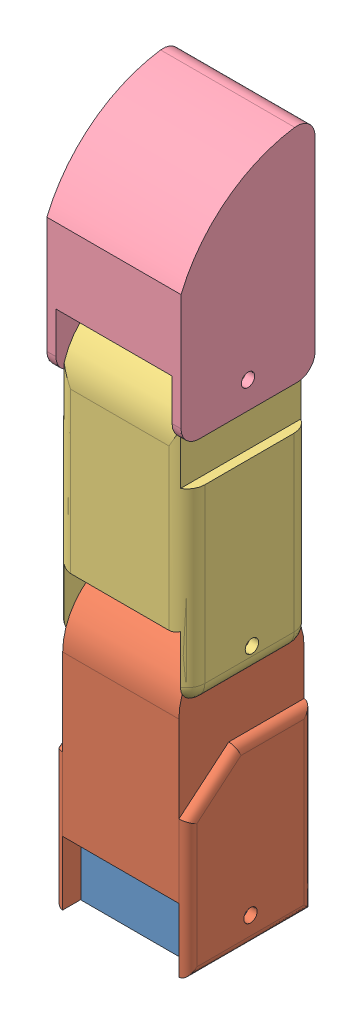
SolidWorks assembly finger_assembly_no_pins_2_moveable_joint, configuration Default. Lengths in mm.
Overall size (15 76.91 15).
4 component instances, 4 part files, 9 mates.
Components (placement in the parent):
- connection_to_motor-1: connection_to_motor [Default] at (-1.3444 3.3196 4.6567) size (13 7.55 9.9)
- end_of_finger-1: end_of_finger [Default] at (-2.3444 3.3736 16.6064) x (0 -1 0) z (1 0 0) size (32 14 15)
- middle_of_finger-1: middle_of_finger [Default] at (12.6556 29.3736 2.7087) x (0 -1 0) z (-1 0 0) size (31.73 14 15)
- tip_of_finger-1: tip_of_finger [Default] at (-2.3444 55.3736 17.3744) x (0 -1 0) z (1 0 0) size (24.86 15 15)
Mates (geometry in assembly coordinates):
- Concentric1: concentric anti-aligned: cylinder of connection_to_motor-1 through (11.6556 6.3736 9.6064) axis (1 0 0) radius 0.75; cylinder of end_of_finger-1 through (-2.3444 6.3736 9.6064) axis (-1 0 0) radius 0.75
- Width1: width anti-aligned: plane of end of finger-1 through (12.6556 28.3736 9.6064) normal (1 0 0); plane of connection to motor-1 through (-2.3444 28.3736 9.6064) normal (-1 0 0); plane of end of finger-1 through (-1.3444 3.8736 9.6064) normal (-1 0 0); plane of connection to motor-1 through (11.6556 3.8736 9.6064) normal (1 0 0)
- Concentric4: concentric anti-aligned: cylinder of middle_of_finger-1 through (-2.3444 32.3736 9.4407) axis (-1 0 0) radius 0.75; cylinder of end_of_finger-1 through (11.6556 32.3736 9.4407) axis (1 0 0) radius 0.75
- Width3: width anti-aligned: plane of middle of finger-1 through (-2.3444 54.3736 9.7087) normal (-1 0 0); plane of end of finger-1 through (12.6556 54.3736 9.7087) normal (1 0 0); plane of middle of finger-1 through (11.6556 28.3736 9.6064) normal (1 0 0); plane of end of finger-1 through (-1.3444 28.3736 9.6064) normal (-1 0 0)
- Concentric6: concentric anti-aligned: cylinder of middle of finger-1 through (-1.3444 58.3736 9.8744) axis (-1 0 0) radius 0.75; cylinder of tip of finger-1 through (12.6556 58.3736 9.8744) axis (1 0 0) radius 0.75
- Width5: width aligned: plane of tip of finger-1 through (12.6556 64.1236 2.3744) normal (1 0 0); plane of middle of finger-1 through (-2.3444 64.1236 2.3744) normal (-1 0 0); plane of tip of finger-1 through (11.6556 54.3736 9.7087) normal (1 0 0); plane of middle of finger-1 through (-1.3444 54.3736 9.7087) normal (-1 0 0)
- LimitAngle3: limit planar angle = 0 rad aligned: plane of connection to motor-1 through (11.6556 8.8234 4.6567) normal (0 0 -1); plane of end of finger-1 through (12.6556 3.3736 2.6064) normal (0 0 -1)
- LimitAngle11: limit planar angle = 0 rad aligned: plane of middle of finger-1 through (-2.3444 29.3736 2.7087) normal (0 0 -1); plane of end of finger-1 through (12.6556 3.3736 2.6064) normal (0 0 -1)
- LimitAngle9: limit planar angle = 0 rad aligned: plane of tip of finger-1 through (12.6556 80.3736 2.3744) normal (0 0 -1); plane of middle of finger-1 through (-2.3444 29.3736 2.7087) normal (0 0 -1)
